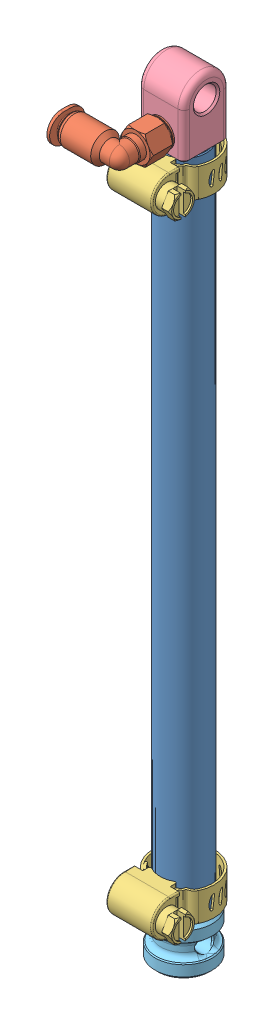
SolidWorks assembly AARL_QR_PN_PA_BL_KN_EX-Extensor, configuration Default. Lengths in mm.
Overall size (26.6 215.9 31.28).
6 component instances, 5 part files, 15 mates.
Components (placement in the parent):
- AARL_QR_PN_PA_BL_KN_EX_001-1: AARL_QR_PN_PA_BL_KN_EX_001 [Resting] at origin size (12.7 184.15 12.7)
- AARL_Puppy_18_02_57_010-QSML-M3-4-1: AARL_Puppy_18_02_57_010-QSML-M3-4 [Default] at (0 96.8375 17.85) x (-1 0 0) z (0 0 -1) size (20.32 8 18.9)
- AARL_Puppy_18_02_57_011-5388K140_Hose-Clamp-1: AARL_Puppy_18_02_57_011-5388K140_Hose-Clamp [5388K14] at (0 87.122 0) x (1 0 0) z (0 -1 0) size (19.43 23.71 9.91)
- AARL_Puppy_18_02_57_011-5388K140_Hose-Clamp-2: AARL_Puppy_18_02_57_011-5388K140_Hose-Clamp [5388K14] at (0 -87.122 0) x (1 0 0) z (0 -1 0) size (19.43 23.71 9.91)
- AARL_QR_PN_EP_001-1: AARL_QR_PN_EP_001 [Default] at (0 104.775 0) x (0 0 1) z (-1 0 0) size (12.7 31.75 12.7)
- AARL_QR_PN_EP_002-1: AARL_QR_PN_EP_002 [Default] at (0 -92.075 0) x (-1 0 0) z (0 0 1) size (15.88 25.4 15.88)
Mates (geometry in assembly coordinates):
- Concentric1: concentric aligned: cylinder of AARL_QR_PN_PA_BL_KN_EX_001-1 through (0 11.6086 0) axis (0 1 0) radius 4.7625; cylinder of AARL_QR_PN_EP_001-1 through (0 114.319 0) axis (0 1 0) radius 4.3656
- Parallel1: parallel aligned: plane of AARL_QR_PN_EP_001-1 through (-6.35 92.075 6.35) normal (0 0 1)
- Coincident2: coincident anti-aligned: plane of AARL_QR_PN_PA_BL_KN_EX_001-1 through (4.7625 92.075 0) normal (0 1 0); plane of AARL_QR_PN_EP_001-1 through (-6.35 92.075 -6.35) normal (0 -1 0)
- Concentric2: concentric aligned: cylinder of AARL_Puppy_18_02_57_010-QSML-M3-4-1 through (0 96.8375 6.35) axis (0 0 1) radius 1.5; cylinder of AARL_QR_PN_EP_001-1 through (0 96.8375 6.35) axis (0 0 1) radius 2.0193
- Parallel2: parallel aligned: plane of AARL_Puppy_18_02_57_010-QSML-M3-4-1 through (2.3094 92.8375 13.4056) normal (0 -1 0); plane of AARL_QR_PN_EP_001-1 through (-6.35 92.075 -6.35) normal (0 -1 0)
- Coincident4: coincident anti-aligned: plane of AARL_Puppy_18_02_57_010-QSML-M3-4-1 through (0 96.8375 6.35) normal (0 0 -1); plane of AARL_QR_PN_EP_001-1 through (-6.35 92.075 6.35) normal (0 0 1)
- Concentric3: concentric aligned: cylinder of AARL_QR_PN_PA_BL_KN_EX_001-1 through (0 11.6086 0) axis (0 1 0) radius 6.35; cylinder of AARL_Puppy_18_02_57_011-5388K140_Hose-Clamp-1 through (0 83.1532 0) axis (0 1 0) radius 7.9375
- Coincident5: coincident aligned: plane of AARL_Puppy_18_02_57_011-5388K140_Hose-Clamp-1 through (6.35 87.122 10.2337) normal (1 0 0); plane of AARL_QR_PN_EP_001-1 through (6.35 104.775 0) normal (1 0 0)
- Coincident6: coincident anti-aligned: plane of AARL_Puppy_18_02_57_011-5388K140_Hose-Clamp-1 through (0 92.075 0) normal (0 1 0); plane of AARL_QR_PN_EP_001-1 through (-6.35 92.075 -6.35) normal (0 -1 0)
- Concentric4: concentric anti-aligned: cylinder of AARL_QR_PN_PA_BL_KN_EX_001-1 through (0 11.6086 0) axis (0 1 0) radius 4.7625; cylinder of AARL_QR_PN_EP_002-1 through (0 -99.8127 0) axis (0 -1 0) radius 4.3656
- Parallel3: parallel anti-aligned: cylinder of AARL_QR_PN_EP_001-1 through (-6.35 104.775 0) axis (1 0 0) radius 3.175; cylinder of AARL_QR_PN_EP_002-1 through (7.9375 -98.425 0) axis (-1 0 0) radius 2.3813
- Coincident7: coincident anti-aligned: plane of AARL_QR_PN_PA_BL_KN_EX_001-1 through (6.35 -92.075 0) normal (0 -1 0); plane of AARL_QR_PN_EP_002-1 through (-4.3656 -92.075 0) normal (0 1 0)
- Concentric6: concentric aligned: cylinder of AARL_QR_PN_PA_BL_KN_EX_001-1 through (0 11.6086 0) axis (0 1 0) radius 6.35; cylinder of AARL_Puppy_18_02_57_011-5388K140_Hose-Clamp-2 through (0 -91.0907 0) axis (0 1 0) radius 7.9375
- Coincident8: coincident aligned: plane of AARL_Puppy_18_02_57_011-5388K140_Hose-Clamp-1 through (6.35 87.122 10.2337) normal (1 0 0); plane of AARL_Puppy_18_02_57_011-5388K140_Hose-Clamp-2 through (6.35 -87.122 10.2337) normal (1 0 0)
- Coincident9: coincident anti-aligned: plane of AARL_Puppy_18_02_57_011-5388K140_Hose-Clamp-2 through (0 -92.075 0) normal (0 -1 0); plane of AARL_QR_PN_EP_002-1 through (-4.3656 -92.075 0) normal (0 1 0)
